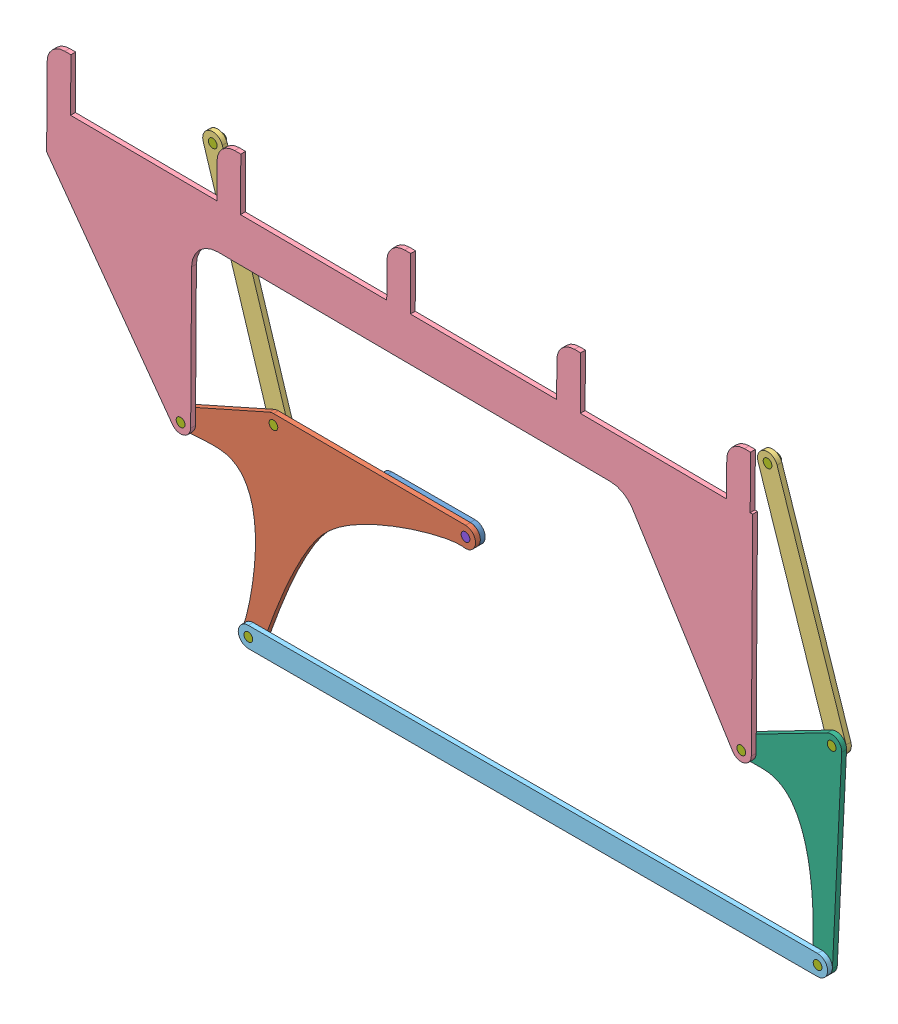
SolidWorks assembly Assem1, configuration Default. Lengths in mm.
Overall size (994.78 489.74 22).
17 component instances, 8 part files, 37 mates.
Components (placement in the parent):
- link_AB-1: link_AB [Default] at (48.8806 -0.003 246.0656) x (0.999997 0.002311 0) z (0 0 1) size (118 23 5.5)
- link_BCEF-1: link_BCEF [Default] at (-122.9349 0.9644 251.5656) x (0.913519 0.406796 0) z (0 0 1) size (333 213 5.5)
- link_CD_JH-1: link_CD_JH [Default] at (-160.3275 120.2405 246.0656) x (-0.299141 0.954209 0) z (0 0 1) size (273 23 5.5)
- link_EI-1: link_EI [Default] at (26.8662 194.6042 257.0656) x (0.999979 -0.006463 0) z (0 0 1) size (805.84 311.5 5.5)
- link_FG-1: link_FG [Default] at (178.869 -217.0551 257.0656) x (1 0.000913 0) z (0 0 1) size (673 23 5.5)
- link_GHI-1: link_GHI [Default] at (514.4752 2.5301 251.5656) x (0.888621 0.458642 0) z (0 0 1) size (133 213 5.5)
- pin-1: pin [Default] at (1.3808 -0.1127 237.8156) size (10 10 11)
- pin-3: pin [Default] at (-122.9349 0.9644 243.3156) x (1 -0.000015 0) z (0 0 1) size (10 10 11)
- pin-4: pin [Default] at (-146.1309 -217.3518 248.8156) x (1 -0.000018 0) z (0 0 1) size (10 10 11)
- pin-5: pin [Default] at (503.8689 -216.7585 248.8156) x (1 -0.000046 0) z (0 0 1) size (10 10 11)
- link_CD_JH-2: link_CD_JH [Default] at (475.1134 121.171 246.0656) x (-0.314894 0.949127 0) z (0 0 1) size (273 23 5.5)
- pin-6: pin [Default] at (-223.422 -43.7831 248.8156) size (10 10 11)
- pin-7: pin [Default] at (416.7269 -47.9205 248.8156) size (10 10 11)
- pin-8: pin [Default] at (514.4752 2.5301 243.3156) x (1 0.00006 0) z (0 0 1) size (10 10 11)
- pin-9: pin [Default] at (-197.7202 239.5166 237.8156) x (0.999963 0.008614 0) z (0 0 1) size (10 10 11)
- pin-11: pin [Default] at (435.7517 239.8118 237.8156) size (10 10 11)
- pin - 1-1: pin - 1 [Default] at (96.3805 0.1068 243.3156) x (-0.662091 -0.749424 0) z (0 0 1) size (10 10 11)
Mates (geometry in assembly coordinates):
- Concentric8: concentric aligned: cylinder of link_BCEF-1 through (-122.9346 0.9645 254.3156) axis (0 0 -1) radius 5; cylinder of pin-3 through (-122.9346 0.9645 254.3156) axis (0 0 -1) radius 5
- Coincident11: coincident aligned: plane of link_BCEF-1 through (-223.4328 -43.7582 254.3156) normal (0 0 1); plane of pin-3 through (-122.9346 0.9645 254.3156) normal (0 0 1)
- Concentric9: concentric aligned: cylinder of link_CD_JH-1 through (-122.9346 0.9645 248.8156) axis (0 0 -1) radius 5; cylinder of pin-3 through (-122.9346 0.9645 254.3156) axis (0 0 -1) radius 5
- Coincident12: coincident aligned: plane of link_CD_JH-1 through (-122.9346 0.9645 243.3156) normal (0 0 -1); plane of pin-3 through (-122.9346 0.9645 243.3156) normal (0 0 -1)
- Concentric10: concentric aligned: cylinder of link_BCEF-1 through (-146.1844 -217.3459 254.3156) axis (0 0 -1) radius 5; cylinder of pin-4 through (-146.1844 -217.3459 259.8156) axis (0 0 -1) radius 5
- Coincident13: coincident aligned: plane of link_BCEF-1 through (-223.4328 -43.7582 248.8156) normal (0 0 -1); plane of pin-4 through (-146.1844 -217.3459 248.8156) normal (0 0 -1)
- Concentric11: concentric aligned: cylinder of link_FG-1 through (-146.1844 -217.3459 259.8156) axis (0 0 -1) radius 5; cylinder of pin-4 through (-146.1844 -217.3459 259.8156) axis (0 0 -1) radius 5
- Coincident14: coincident aligned: plane of link_FG-1 through (-146.1844 -217.3459 259.8156) normal (0 0 1); plane of pin-4 through (-146.1844 -217.3459 259.8156) normal (0 0 1)
- Concentric12: concentric aligned: cylinder of link_FG-1 through (503.8153 -216.7551 259.8156) axis (0 0 -1) radius 5; cylinder of pin-5 through (503.8153 -216.7551 259.8156) axis (0 0 -1) radius 5
- Coincident15: coincident aligned: plane of link_FG-1 through (-146.1844 -217.3459 259.8156) normal (0 0 1); plane of pin-5 through (503.8153 -216.7551 259.8156) normal (0 0 1)
- Concentric13: concentric aligned: cylinder of link_GHI-1 through (503.8153 -216.7551 254.3156) axis (0 0 -1) radius 5; cylinder of pin-5 through (503.8153 -216.7551 259.8156) axis (0 0 -1) radius 5
- Coincident16: coincident aligned: plane of link_GHI-1 through (514.4773 2.5308 248.8156) normal (0 0 -1); plane of pin-5 through (503.8153 -216.7551 248.8156) normal (0 0 -1)
- Concentric14: concentric aligned: cylinder of link_BCEF-1 through (-223.4328 -43.7582 254.3156) axis (0 0 -1) radius 5; cylinder of pin-6 through (-223.4328 -43.7582 259.8156) axis (0 0 -1) radius 5
- Coincident17: coincident aligned: plane of link_BCEF-1 through (-223.4328 -43.7582 248.8156) normal (0 0 -1); plane of pin-6 through (-223.4328 -43.7582 248.8156) normal (0 0 -1)
- Concentric15: concentric aligned: cylinder of link_EI-1 through (-223.4328 -43.7582 259.8156) axis (0 0 -1) radius 5; cylinder of pin-6 through (-223.4328 -43.7582 259.8156) axis (0 0 -1) radius 5
- Coincident18: coincident aligned: plane of link_EI-1 through (-223.4328 -43.7582 259.8156) normal (0 0 1); plane of pin-6 through (-223.4328 -43.7582 259.8156) normal (0 0 1)
- Concentric16: concentric aligned: cylinder of link_GHI-1 through (416.7162 -47.895 254.3156) axis (0 0 -1) radius 5; cylinder of pin-7 through (416.7162 -47.895 259.8156) axis (0 0 -1) radius 5
- Coincident19: coincident aligned: plane of link_GHI-1 through (514.4773 2.5308 248.8156) normal (0 0 -1); plane of pin-7 through (416.7162 -47.895 248.8156) normal (0 0 -1)
- Concentric17: concentric aligned: cylinder of link_EI-1 through (416.7162 -47.895 259.8156) axis (0 0 -1) radius 5; cylinder of pin-7 through (416.7162 -47.895 259.8156) axis (0 0 -1) radius 5
- Coincident20: coincident aligned: plane of link_EI-1 through (-223.4328 -43.7582 259.8156) normal (0 0 1); plane of pin-7 through (416.7162 -47.895 259.8156) normal (0 0 1)
- Concentric18: concentric aligned: cylinder of link_GHI-1 through (514.4773 2.5308 254.3156) axis (0 0 -1) radius 5; cylinder of pin-8 through (514.4773 2.5308 254.3156) axis (0 0 -1) radius 5
- Coincident21: coincident aligned: plane of link_GHI-1 through (514.4773 2.5308 254.3156) normal (0 0 1); plane of pin-8 through (514.4773 2.5308 254.3156) normal (0 0 1)
- Concentric19: concentric aligned: cylinder of link_CD_JH-2 through (514.4773 2.5308 248.8156) axis (0 0 -1) radius 5; cylinder of pin-8 through (514.4773 2.5308 254.3156) axis (0 0 -1) radius 5
- Coincident22: coincident aligned: plane of link_CD_JH-2 through (514.4773 2.5308 243.3156) normal (0 0 -1); plane of pin-8 through (514.4773 2.5308 243.3156) normal (0 0 -1)
- Concentric20: concentric aligned: cylinder of link_CD_JH-1 through (-197.7202 239.5166 248.8156) axis (0 0 -1) radius 5; cylinder of pin-9 through (-197.7202 239.5166 248.8156) axis (0 0 -1) radius 5
- Coincident23: coincident aligned: plane of link_CD_JH-1 through (-122.9346 0.9645 248.8156) normal (0 0 1); plane of pin-9 through (-197.7202 239.5166 248.8156) normal (0 0 1)
- Concentric22: concentric aligned: cylinder of link_CD_JH-2 through (435.7517 239.8118 248.8156) axis (0 0 -1) radius 5; cylinder of pin-11 through (435.7517 239.8118 248.8156) axis (0 0 -1) radius 5
- Coincident24: coincident aligned: plane of link_CD_JH-2 through (514.4773 2.5308 248.8156) normal (0 0 1); plane of pin-11 through (435.7517 239.8118 248.8156) normal (0 0 1)
- Coincident35: coincident aligned: plane of link_AB-1 through (1.3808 -0.1127 248.8156) normal (0 0 1); plane of pin-1 through (1.3808 -0.1127 248.8156) normal (0 0 1)
- Concentric23: concentric: cylinder of link_AB-1 through (96.3777 0.6535 248.8156) axis (0 0 -1) radius 5; cylinder of pin-1 through (1.3808 -0.1127 248.8156) axis (0 0 -1) radius 5
- Coincident36: coincident aligned: plane of link_AB-1 through (1.3808 -0.1127 248.8156) normal (0 0 1); plane of pin-1 through (1.3808 -0.1127 248.8156) normal (0 0 1)
- Concentric27: concentric aligned: cylinder of link_AB-1 through (1.3808 -0.1127 248.8156) axis (0 0 -1) radius 5; cylinder of pin-1 through (1.3808 -0.1127 248.8156) axis (0 0 -1) radius 5
- Coincident42: coincident aligned: plane of link_AB-1 through (1.3808 -0.1127 248.8156) normal (0 0 1); plane of pin-1 through (1.3808 -0.1127 248.8156) normal (0 0 1)
- Concentric28: concentric aligned: cylinder of link_AB-1 through (96.3806 0.0527 248.8156) axis (0 0 -1) radius 5; cylinder of pin - 1-1 through (96.3806 0.0527 254.3156) axis (0 0 -1) radius 5
- Coincident43: coincident aligned: plane of link_AB-1 through (1.3808 -0.1127 243.3156) normal (0 0 -1); plane of pin - 1-1 through (96.3806 0.0527 243.3156) normal (0 0 -1)
- Coincident44: coincident aligned: plane of link_BCEF-1 through (-223.4328 -43.7582 254.3156) normal (0 0 1); plane of pin - 1-1 through (96.3806 0.0527 254.3156) normal (0 0 1)
- Coincident45: coincident aligned: circle of link_BCEF-1; circle of pin - 1-1
